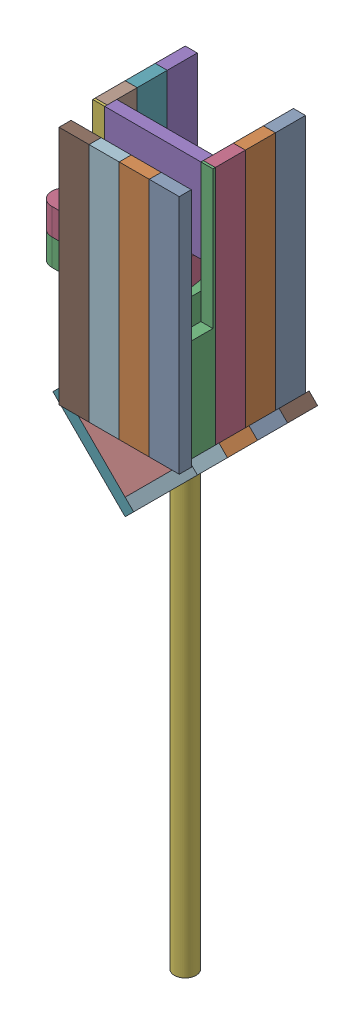
SolidWorks assembly Beach Hut Green_1, configuration Défaut. Lengths in mm.
Overall size (132.1 615 113.42).
11 component instances, 11 part files, 0 mates.
Components (placement in the parent):
- Beach hut - Wall 1-1: Beach hut - Wall 1 [Défaut] at (-258.4913 -116.3682 161.3389) x (0 0 1) z (0 -1 0) size (100 10 210)
- Beach hut - Wall 2-1: Beach hut - Wall 2 [Défaut] at (-358.4913 -116.3682 161.3389) x (0 0 1) z (0 -1 0) size (100 10 210)
- Beach hut - Wall back-1: Beach hut - Wall back [Défaut] at (-308.4913 -161.3682 148.8389) x (-1 0 0) z (0 0 1) size (80 100 10)
- Beach hut - Wall front-1: Beach hut - Wall front [Défaut] at (-308.4913 -126.3682 238.8389) x (-1 0 0) z (0 0 1) size (80 135 10)
- Beach hut - door-1: Beach hut - door [Défaut] at (-340.9913 -112.3682 258.8389) x (1 0 0) z (0 1 0) size (100 10 200)
- Beach hut - Ground-1: Beach hut - Ground [Défaut] at (-308.4913 -126.3682 198.8389) size (112 22 100)
- Beach hut - Door 2-1: Beach hut - Door 2 [Défaut] at (-369.4913 -82.3682 237.8389) x (0 0 1) z (1 0 0) size (103.42 22 106)
- Beach hut - Wall 3-1: Beach hut - Wall 3 [Défaut] at (-308.4913 -81.3682 215.8389) size (80 70 10)
- Beach hut - Matt-1: Beach hut - Matt [Défaut] at (-308.4913 -626.3682 198.8389) x (-0.87546 0 0.48329) z (-0.48329 0 -0.87546) size (18 500 18)
- Beach hut - Roof 2-1: Beach hut - Roof 2 [Défaut] at (-338.5433 -245.4583 161.3389) x (0 0 1) z (-0.707107 0.707107 0) size (100 10 85)
- Beach hut - Roof 1-1: Beach hut - Roof 1 [Défaut] at (-281.9748 -234.8517 161.3389) x (0 0 1) z (0.707107 0.707107 0) size (100 10 75)
